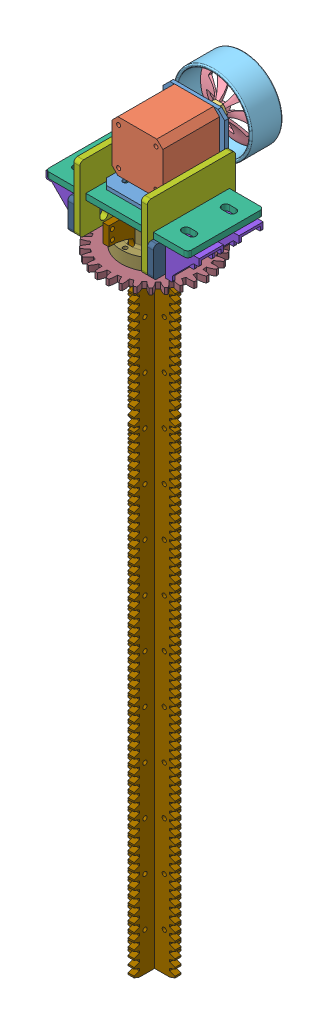
SolidWorks assembly 装配体1, configuration 默认. Lengths in mm.
Overall size (127 635.17 117.51).
22 component instances, 13 part files, 40 mates.
Components (placement in the parent):
- 电机支架-1: 电机支架 [默认] at (0.5477 -19.153 31) size (51 51 56)
- 电机驱动器-1: 电机驱动器 [默认] at (0.5477 7.847 31) size (42.3 42.3 71)
- 六角联轴器-1: 六角联轴器 [默认] at (0.5477 7.847 16) x (1 0 0) z (0 1 0) size (14 18 12.12)
- 整个车轮-1: 整个车轮 [默认] at (-1.2111 6.0898 64.1725) x (-0.823184 -0.567775 0) z (0 0 -1) size (84.94 84.94 26)
  - 轮胎-1: 轮胎 [默认] at (-2.4455 0.4479 54.1725) size (63.39 63.18 21.57)
  - 轮胎外-1: 轮胎外 [默认] at (-2.4455 0.4479 48.1725) x (0.923728 0.383049 0) z (0.383049 -0.923728 0) size (65 26 65)
- 1-1: 1 [默认] at (0.5477 -27.153 60.15) x (1 0 0) z (0 1 0) size (118 63 5)
- 2-1: 2 [默认] at (31.0477 -24.653 63.65) x (0 0 -1) z (-1 0 0) size (73 55 5)
- 2-2: 2 [默认] at (-24.9523 -24.653 63.65) x (0 0 -1) z (-1 0 0) size (73 55 5)
- 2020角件-1: 2020角件 [Default] at (36.0477 -27.153 37.15) x (0 -1 0) z (0 0 1) size (28 28 20)
- 2020角件-2: 2020角件 [Default] at (-34.9523 -27.153 90.15) x (0 -1 0) z (0 0 -1) size (28 28 20)
- 3-1: 3 [默认] at (-1.9523 -27.153 66.15) x (1 0 0) z (0 0 -1) size (38 552.15 5)
- 3-2: 3 [默认] at (3.0477 -27.153 61.15) x (-1 0 0) z (0 0 1) size (38 552.15 5)
- 4-1: 4 [默认] at (-29.9523 -39.653 63.65) x (0 0 -1) z (-1 0 0) size (73 25 5)
- 2020角件-3: 2020角件 [Default] at (-34.9523 -27.153 57.15) x (0 -1 0) z (0 0 -1) size (28 28 20)
- 4-2: 4 [默认] at (36.0477 -39.653 63.65) x (0 0 -1) z (-1 0 0) size (73 25 5)
- 2020角件-4: 2020角件 [Default] at (36.0477 -27.153 70.15) x (0 -1 0) z (0 0 1) size (28 28 20)
- 7-1: 7 [默认] at (0.5477 -137.153 61.15) size (5 220 5)
- 3-3: 3 [默认] at (3.0477 -27.153 66.15) x (0 0 -1) z (-1 0 0) size (38 552.15 5)
- 3-4: 3 [默认] at (-1.9523 -27.153 61.15) x (0 0 1) z (1 0 0) size (38 552.15 5)
- 8-1: 8 [默认] at (0.5477 -62.153 63.65) x (1 0 0) z (0 1 0) size (55 55 26)
- 齿轮4-1: 齿轮4 [默认] at (0.5477 -62.153 63.6502) x (1 0 0) z (0 -1 0) size (88 87.71 5)
Mates (geometry in assembly coordinates):
- 同心1: concentric aligned: cylinder of 电机支架-1 through (0.5477 7.847 28) axis (0 0 1) radius 11; cylinder of 电机驱动器-1 through (0.5477 7.847 29) axis (0 0 1) radius 11
- 重合1: coincident anti-aligned: plane of 电机支架-1 through (0.5477 -19.153 31) normal (0 0 1); plane of 电机驱动器-1 through (0.5477 7.847 31) normal (0 0 -1)
- 同心2: concentric anti-aligned: cylinder of 电机支架-1 through (-14.9523 23.347 28) axis (0 0 1) radius 1.65; cylinder of 电机驱动器-1 through (-14.9523 23.347 78) axis (0 0 -1) radius 1.65
- 同心3: concentric anti-aligned: cylinder of 电机支架-1 through (16.0477 -7.653 28) axis (0 0 1) radius 1.65; cylinder of 电机驱动器-1 through (16.0477 -7.653 78) axis (0 0 -1) radius 1.65
- 同心4: concentric anti-aligned: cylinder of 电机驱动器-1 through (0.5477 7.847 7) axis (0 0 1) radius 2.5; cylinder of 六角联轴器-1 through (0.5477 7.847 39) axis (0 0 -1) radius 2.5
- 重合2: coincident anti-aligned: plane of 电机支架-1 through (0.5477 -19.153 28) normal (0 0 -1); plane of 六角联轴器-1 through (0.5477 7.847 28) normal (0 0 1)
- 同心5: concentric anti-aligned: cylinder of 六角联轴器-1 through (0.5477 7.847 28) axis (0 0 -1) radius 5.75; cylinder of 整个车轮-1/轮胎外-1 through (0.5477 7.847 -10) axis (0 0 1) radius 32.5
- 重合4: coincident anti-aligned: plane of 六角联轴器-1 through (0.5477 7.847 10) normal (0 0 -1); plane of 整个车轮-1/轮胎-1 through (5.4868 11.2537 10) normal (0 0 1)
- 重合5: coincident anti-aligned: plane of 电机支架-1 through (0.5477 -22.153 31) normal (0 -1 0); plane of 1-1 through (56.5477 -22.153 35.15) normal (0 1 0)
- 重合6: coincident aligned: plane of 电机支架-1 through (13.3977 -22.153 43.15) normal (1 0 0); plane of 1-1 through (13.3977 -22.153 77.15) normal (1 0 0)
- 同心6: concentric anti-aligned: cylinder of 电机支架-1 through (15.5477 -22.153 43.15) axis (0 1 0) radius 2.15; cylinder of 1-1 through (15.5477 -22.153 43.15) axis (0 -1 0) radius 2.15
- 重合8: coincident anti-aligned: plane of 1-1 through (56.5477 -22.153 35.15) normal (0 1 0); plane of 2-1 through (26.0477 -22.153 95.15) normal (0 -1 0)
- 重合9: coincident anti-aligned: plane of 1-1 through (-55.4523 -22.153 95.15) normal (0 0 1); plane of 2-1 through (26.0477 -27.153 95.15) normal (0 0 -1)
- 重合10: coincident anti-aligned: plane of 电机支架-1 through (26.0477 -22.153 28) normal (1 0 0); plane of 2-1 through (26.0477 -49.153 30.15) normal (-1 0 0)
- 重合12: coincident anti-aligned: plane of 1-1 through (56.5477 -27.153 35.15) normal (0 -1 0); plane of 2020角件-1 through (36.0477 -27.153 57.15) normal (0 1 0)
- 重合13: coincident aligned: plane of 1-1 through (48.2977 -32.153 50.4) normal (0 0 -1); plane of 2020角件-1 through (47.0477 -27.152 50.4) normal (0 0 -1)
- 重合14: coincident anti-aligned: plane of 1-1 through (56.5477 -27.153 35.15) normal (0 -1 0); plane of 2020角件-2 through (-34.9523 -27.153 70.15) normal (0 1 0)
- 重合16: coincident aligned: plane of 2-2 through (-29.9523 -45.653 76.9) normal (0 0 1); plane of 2020角件-2 through (-34.9513 -37.153 76.9) normal (0 0 1)
- 重合17: coincident anti-aligned: plane of 1-1 through (56.5477 -27.153 35.15) normal (0 -1 0); plane of 3-1 through (-1.9523 -27.153 61.15) normal (0 1 0)
- 重合18: coincident anti-aligned: plane of 2-2 through (-29.9523 -42.153 66.15) normal (0 0 -1); plane of 3-1 through (-38.7372 -87.6335 66.15) normal (0 0 1)
- 距离1: distance = 10 mm aligned: plane of 3-1 through (-39.9523 -27.153 61.15) normal (-1 0 0); plane of 2-2 through (-29.9523 -49.153 30.15) normal (-1 0 0)
- 重合21: coincident anti-aligned: plane of 2-2 through (-29.9523 -49.153 30.15) normal (-1 0 0); plane of 4-1 through (-29.9523 -30.153 30.15) normal (1 0 0)
- 重合22: coincident aligned: plane of 2-2 through (-29.9523 -37.153 43.9) normal (0 0 1); plane of 4-1 through (-34.9523 -37.153 43.9) normal (0 0 1)
- 重合23: coincident anti-aligned: plane of 2020角件-2 through (-34.9523 -55.153 70.15) normal (1 0 0); plane of 4-1 through (-34.9523 -30.153 30.15) normal (-1 0 0)
- 重合24: coincident anti-aligned: plane of 2020角件-1 through (36.0477 -55.153 57.15) normal (-1 0 0); plane of 4-2 through (36.0477 -30.153 30.15) normal (1 0 0)
- 重合25: coincident anti-aligned: plane of 3-2 through (3.0477 -372.4862 66.15) normal (-1 0 0); plane of 7-1 through (3.0477 -247.153 66.15) normal (1 0 0)
- 重合26: coincident aligned: plane of 3-2 through (39.8326 -87.6335 66.15) normal (0 0 1); plane of 7-1 through (0.5477 -137.153 66.15) normal (0 0 1)
- 重合28: coincident anti-aligned: plane of 1-1 through (56.5477 -27.153 35.15) normal (0 -1 0); plane of 7-1 through (3.0477 -27.153 66.15) normal (0 1 0)
- 重合29: coincident anti-aligned: plane of 1-1 through (56.5477 -27.153 35.15) normal (0 -1 0); plane of 3-3 through (-1.9523 -27.153 66.15) normal (0 1 0)
- 重合30: coincident anti-aligned: plane of 7-1 through (0.5477 -137.153 66.15) normal (0 0 1); plane of 3-3 through (-1.9523 -372.4862 66.15) normal (0 0 -1)
- 重合31: coincident aligned: line of 7-1 through (-1.9523 -27.153 66.15) axis (0 -1 0); line of 3-3 through (-1.9523 -27.153 66.15) axis (0 -1 0)
- 重合32: coincident anti-aligned: plane of 1-1 through (56.5477 -27.153 35.15) normal (0 -1 0); plane of 3-4 through (3.0477 -27.153 61.15) normal (0 1 0)
- 重合33: coincident anti-aligned: plane of 7-1 through (0.5477 -137.153 61.15) normal (0 0 -1); plane of 3-4 through (3.0477 -372.4862 61.15) normal (0 0 1)
- 重合34: coincident aligned: line of 3-1 through (-1.9523 -27.153 61.15) axis (0 -1 0); line of 3-4 through (-1.9523 -27.153 61.15) axis (0 -1 0)
- 重合36: coincident anti-aligned: plane of 3-4 through (3.0477 -87.6335 24.3651) normal (1 0 0); plane of 8-1 through (3.0477 -36.153 58.15) normal (-1 0 0)
- 重合38: coincident anti-aligned: plane of 3-1 through (-38.7372 -87.6335 66.15) normal (0 0 1); plane of 8-1 through (-4.9523 -36.153 66.15) normal (0 0 -1)
- 重合39: coincident anti-aligned: plane of 2-2 through (-29.9523 -52.153 30.15) normal (0 -1 0); plane of 8-1 through (0.5477 -52.153 63.65) normal (0 1 0)
- 同心10: concentric anti-aligned: cylinder of 8-1 through (25.0079 -72.153 63.65) axis (0 1 0) radius 1.75; cylinder of 齿轮4-1 through (25.0077 -57.153 63.6502) axis (0 -1 0) radius 1.75
- 同心11: concentric anti-aligned: cylinder of 8-1 through (0.5477 -72.153 88.1102) axis (0 1 0) radius 1.75; cylinder of 齿轮4-1 through (0.5477 -57.153 88.1102) axis (0 -1 0) radius 1.75
- 重合44: coincident anti-aligned: plane of 8-1 through (0.5477 -62.153 63.65) normal (0 -1 0); plane of 齿轮4-1 through (-18.1416 -62.153 70.6811) normal (0 1 0)
